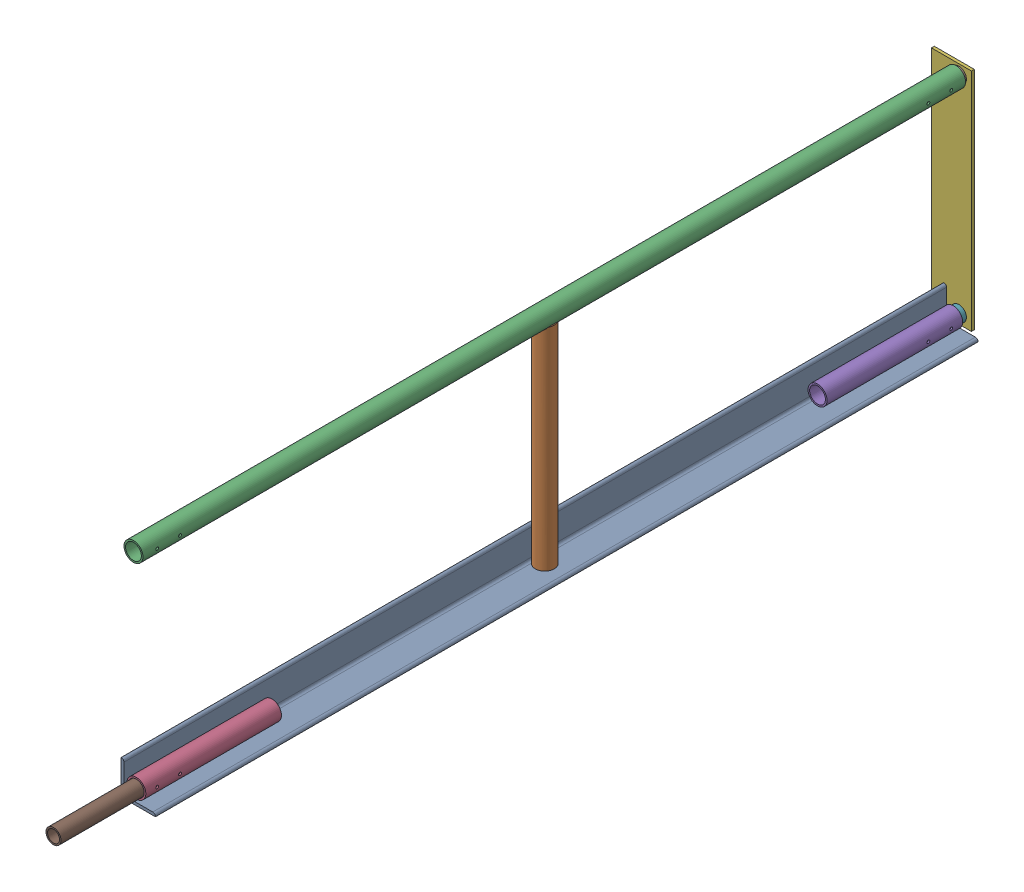
SolidWorks assembly FE-00023_ASM, configuration Default. Lengths in mm.
Overall size (109.88 508 2063.85).
13 component instances, 9 part files, 0 mates.
Components (placement in the parent):
- FE-00005_ASM-1: FE-00005_ASM [Default] at origin size (76.2 507.65 1828.8)
  - FE-00005-01-1: FE-00005-01 [Default] at origin size (76.2 76.2 1828.8)
  - FE-00005-03-1: FE-00005-03 [Default] at (27.432 6.35 914.4) size (42.16 471.23 42.16)
  - FE-00005-04-1: FE-00005-04 [Default] at (27.432 486.5688 0) size (42.16 42.16 1828.8)
  - FE-00005-02-1: FE-00005-02 [Default] at (27.432 27.432 1520.825) size (42.16 42.16 301.62)
  - FE-00005-02-2: FE-00005-02 [Default] at (27.432 27.432 307.975) x (1 0 0) z (0 0 -1) size (42.16 42.16 301.62)
- FE-00018_ASM-1: FE-00018_ASM [Default] at (-33.6804 508 -6.35) x (1 0 0) z (0 0 -1) size (88.9 501.65 152.5)
  - FE-00018-03-1: FE-00018-03 [Default] at origin size (88.9 501.65 6.35)
  - FE-00018-02-1: FE-00018-02 [Default] at (61.1187 480.2188 -101.6) size (33.4 33.4 101.6)
  - FE-00018-02-2: FE-00018-02 [Default] at (61.1124 21.4312 -101.6) size (33.4 33.4 101.6)
  - FE-00018-01-1: FE-00018-01 [Default] at (23.368 63.5 29.8196) x (1 0 0) z (0 1 0) size (42.16 42.16 374.65)
  - FE-00018-04-1: FE-00018-04 [Default] at (23.368 250.825 6.35) size (19.05 374.65 2.38)
- FE-00026-1: FE-00026 [Default] at (27.432 27.432 1651) size (33.4 33.4 355.6)
